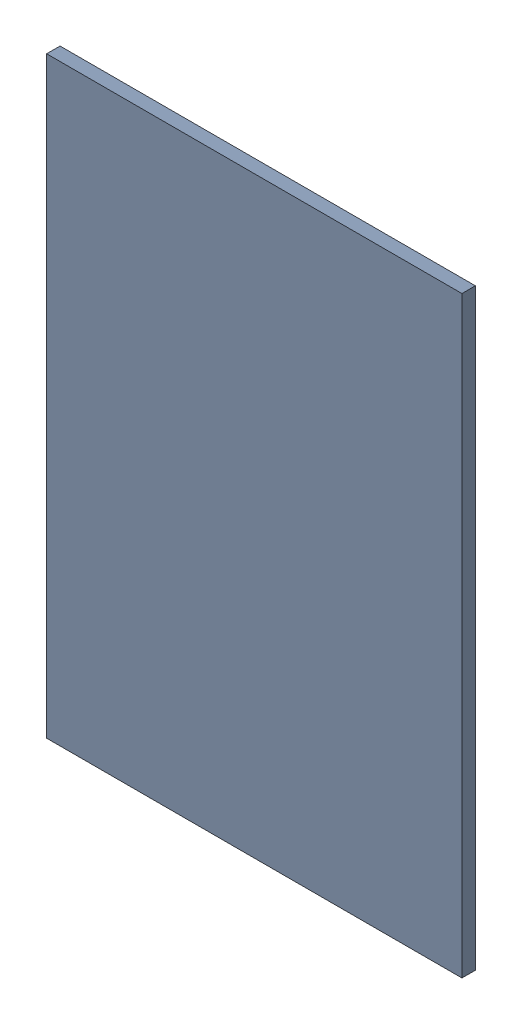
SolidWorks assembly Pad C1-1(28.81mm,46mm) on Top Layer, configuration Predeterminado. Lengths in mm.
Overall size (1.1 1.57 0.04).
2 component instances, 1 part files, 0 mates.
Components (placement in the parent):
- Pad C1-1(28.81mm,46mm) on Top Layer-1-1: Pad C1-1(28.81mm,46mm) on Top Layer-1 [Predeterminado] at (-68.317 -44.187 -0.0457) size (1.1 1.57 0.04)
  - Pad C1-1(28.81mm,46mm) on Top Layer-Part-1-1: Pad C1-1(28.81mm,46mm) on Top Layer-Part-1 [Predeterminado] at origin size (1.1 1.57 0.04)
